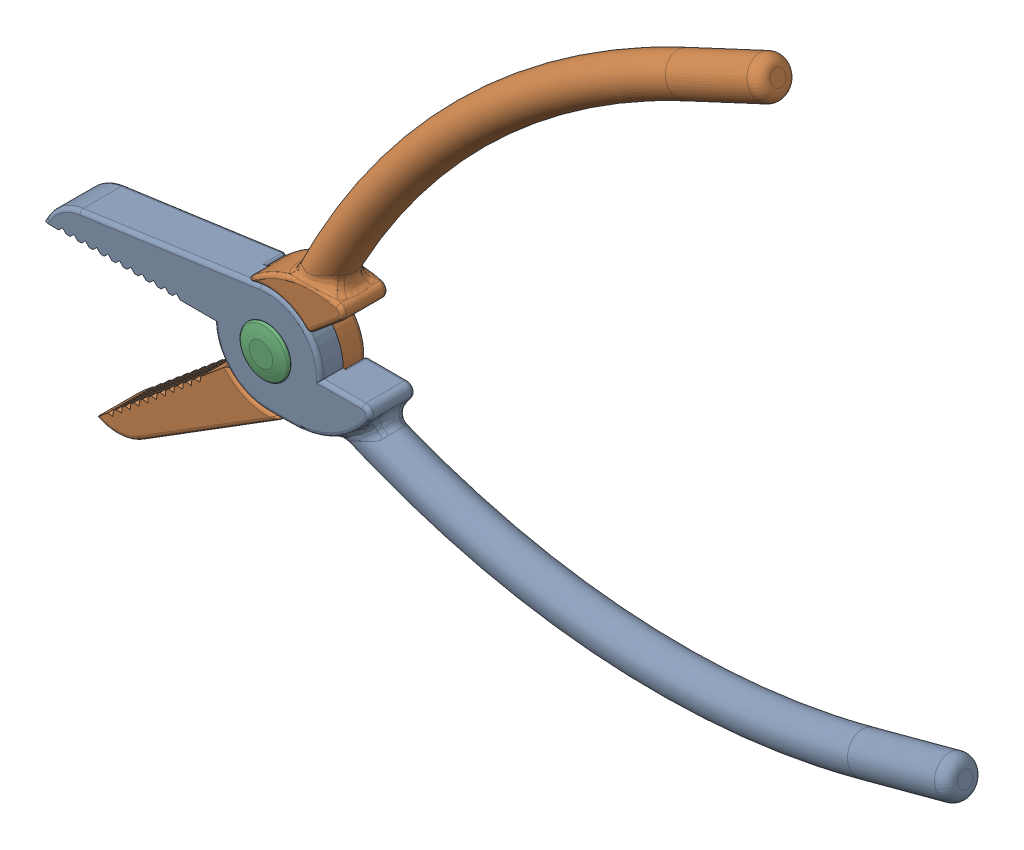
SolidWorks assembly Assem1, configuration Default. Lengths in mm.
Overall size (243.58 187.01 15.4).
3 component instances, 3 part files, 5 mates.
Components (placement in the parent):
- Plier-Handle-Base-1: Plier-Handle-Base [Default] at origin size (237.62 44.74 12.21)
- Plier-Handle-1: Plier-Handle [Default] x (0.766044 0.642788 0) z (0 0 -1) size (237.62 44.74 12.21)
- Plier-Joint-1: Plier-Joint [Default] at origin size (13 13 15.4)
Mates (geometry in assembly coordinates):
- Concentric1: concentric aligned: cylinder of Plier-Handle-Base-1 through (0 0 6) axis (0 0 -1) radius 3; cylinder of Plier-Joint-1 through (0 0 -7.946) axis (0 0 -1) radius 2.5
- Coincident1: coincident anti-aligned: plane of Plier-Handle-Base-1 through (0 0 6) normal (0 0 1); plane of Plier-Joint-1 through (0 0 6) normal (0 0 -1)
- Concentric2: concentric anti-aligned: cylinder of Plier-Handle-1 through (0 0 -6) axis (0 0 1) radius 3; cylinder of Plier-Joint-1 through (0 0 -7.946) axis (0 0 -1) radius 2.5
- Coincident2: coincident anti-aligned: plane of Plier-Handle-1 through (0 0 -6) normal (0 0 -1); plane of Plier-Joint-1 through (0 0 -6) normal (0 0 1)
- Angle1: planar angle = 0.698132 rad anti-aligned: plane of Plier-Handle-Base-1 through (0 0 6) normal (0 1 0); plane of Plier-Handle-1 through (0 0 -6) normal (0.642788 -0.766044 0)
